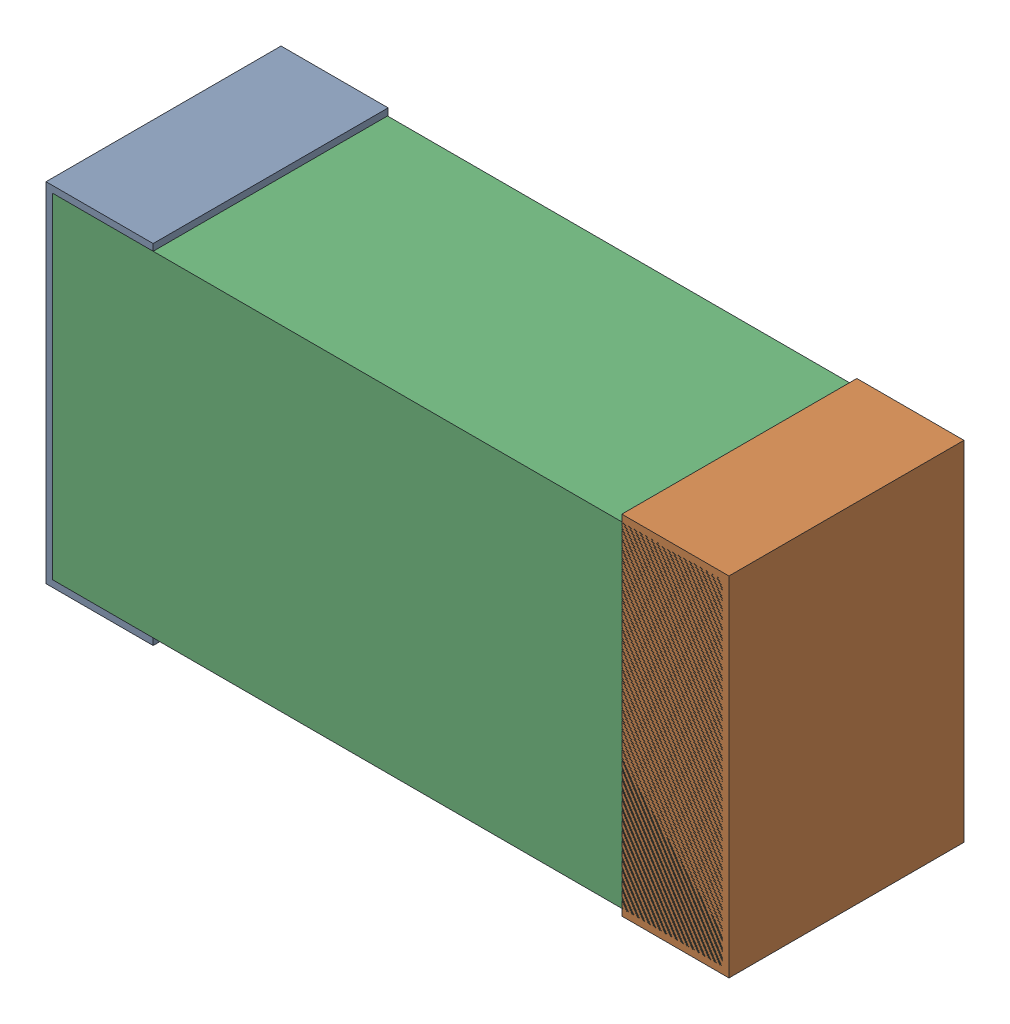
SolidWorks assembly C28, configuration Default. Lengths in mm.
Overall size (1.02 0.52 0.35).
6 component instances, 2 part files, 0 mates.
Components (placement in the parent):
- 870940480-1: 870940480 [Default] at (25.782 24.077 -1.9516) size (0.16 0.52 0.35)
  - Extruded-1: Extruded [Default] at origin size (0.16 0.52 0.35)
- 870940480-2: 870940480 [Default] at (26.642 24.077 -1.9516) size (0.16 0.52 0.35)
  - Extruded-1: Extruded [Default] at origin size (0.16 0.52 0.35)
- 870940640-1: 870940640 [Default] at (26.212 24.077 -1.9506) size (1 0.5 0.35)
  - Extruded_2-1: Extruded_2 [Default] at origin size (1 0.5 0.35)
